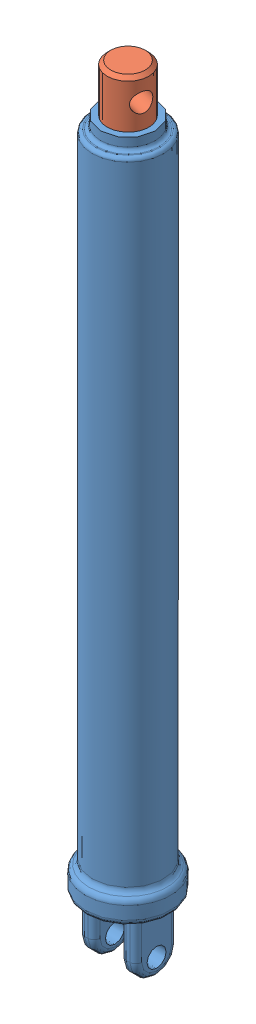
SolidWorks assembly Jack asm, configuration Default. Lengths in mm.
2 component instances, 2 part files, 2 mates.
Components (placement in the parent):
- Cylinder-1: Cylinder [Default] at origin size (71.65 615 71.65)
- Jack rod-1: Jack rod [Default] at (0 55 0) x (-0.258885 0 0.965908) z (-0.965908 0 -0.258885) size (28 550 28)
Mates (geometry in assembly coordinates):
- Concentric1: concentric: cylinder of Cylinder-1 through (0 40 0) axis (0 1 0) radius 17.5; cylinder of Jack rod-1 through (0 605 0) axis (0 -1 0) radius 14
- LimitDistance1: limit distance = 15 mm: plane of Cylinder-1 through (-17.5 40 0) normal (0 1 0); plane of Jack rod-1 through (0 55 0) normal (0 -1 0)
